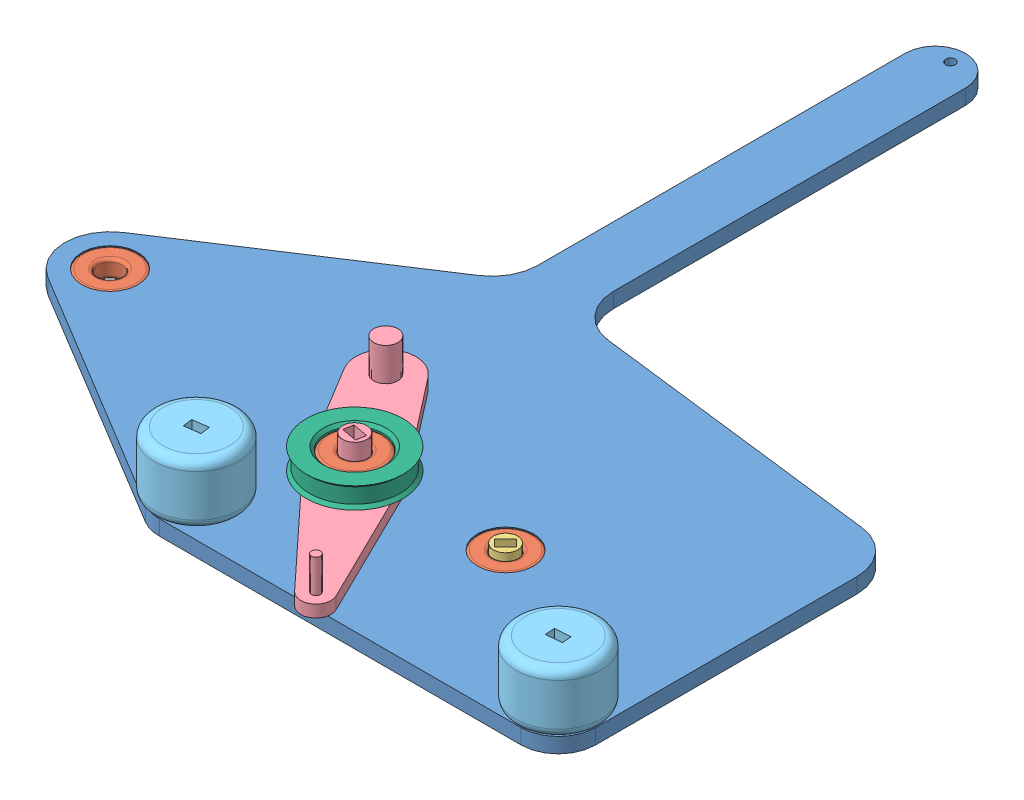
SolidWorks assembly Assem1, configuration Default. Lengths in mm.
Overall size (230.05 31.3 274.17).
13 component instances, 6 part files, 25 mates.
Components (placement in the parent):
- base-1: base [Default] at (141.595 152.7779 330.5532) size (227.3 5 267.3)
- bearing-1: bearing [Default] at (1.595 151.7779 264.2049) size (19 6 19)
- bearing-2: bearing [Default] at (106.2397 151.7779 287.6979) size (19 6 19)
- bearing-3: bearing [Default] at (147.959 151.7779 279.4172) size (19 6 19)
- bearing-4: bearing [Default] at (81.595 151.7779 315.5532) size (19 6 19)
- bearing-5: bearing [Default] at (201.595 151.7779 315.5532) size (19 6 19)
- gear1-1: gear1 [Default] at (106.2397 146.7779 287.6979) x (0.182046 0 -0.98329) z (0.98329 0 0.182046) size (43.58 13 43.58)
- lever1-1: lever1 [Default] at (133.2026 159.7779 336.2734) x (0.98329 0 0.182046) z (-0.182046 0 0.98329) size (78.64 15 78.64)
- wheel-1: wheel [Default] at (81.595 158.0779 315.5532) x (0.991532 0 -0.129866) z (0.129866 0 0.991532) size (28 20 28)
- wheel-2: wheel [Default] at (201.595 158.0779 315.5532) x (0.996928 0 -0.07832) z (0.07832 0 0.996928) size (28 20 28)
- gear1-2: gear1 [Default] at (147.959 146.7779 279.4172) x (0.699396 0 0.714735) z (-0.714735 0 0.699396) size (43.58 13 43.58)
- wheel2-1: wheel2 [Default] at (106.2397 167.2779 287.6979) x (0.999971 0 0.007616) z (-0.007616 0 0.999971) size (32 7 32)
- bearing-6: bearing [Default] at (106.2397 163.7779 287.6979) x (0.996495 0 0.08365) z (-0.08365 0 0.996495) size (19 6 19)
Mates (geometry in assembly coordinates):
- Coincident1: coincident: plane of bearing-5 through (201.595 157.7779 315.5532) normal (0 1 0); plane of base-1 through (81.595 157.7779 315.5532) normal (0 1 0)
- Coincident2: coincident: plane of base-1 through (81.595 157.7779 315.5532) normal (0 1 0); plane of bearing-3 through (147.959 157.7779 279.4172) normal (0 1 0)
- Coincident3: coincident: plane of base-1 through (81.595 157.7779 315.5532) normal (0 1 0); plane of bearing-4 through (81.595 157.7779 315.5532) normal (0 1 0)
- Coincident4: coincident: plane of base-1 through (81.595 157.7779 315.5532) normal (0 1 0); plane of bearing-1 through (1.595 157.7779 264.2049) normal (0 1 0)
- Coincident5: coincident: plane of base-1 through (81.595 157.7779 315.5532) normal (0 1 0); plane of bearing-2 through (106.2397 157.7779 287.6979) normal (0 1 0)
- Concentric1: concentric: cylinder of base-1 through (1.595 157.7779 264.2049) axis (0 -1 0) radius 9.3; cylinder of bearing-1 through (1.595 157.7779 264.2049) axis (0 -1 0) radius 4
- Concentric2: concentric: cylinder of base-1 through (106.2397 157.7779 287.6979) axis (0 -1 0) radius 9.3; cylinder of bearing-2 through (106.2397 157.7779 287.6979) axis (0 -1 0) radius 4
- Concentric3: concentric: cylinder of base-1 through (81.595 157.7779 315.5532) axis (0 -1 0) radius 9.3; cylinder of bearing-4 through (81.595 157.7779 315.5532) axis (0 -1 0) radius 4
- Concentric4: concentric: cylinder of base-1 through (147.959 157.7779 279.4172) axis (0 -1 0) radius 9.3; cylinder of bearing-3 through (147.959 157.7779 279.4172) axis (0 -1 0) radius 4
- Concentric5: concentric: cylinder of base-1 through (201.595 157.7779 315.5532) axis (0 -1 0) radius 9.3; circle of bearing-5
- Distance1: distance = 6 mm aligned: plane of base-1 through (81.595 157.7779 315.5532) normal (0 1 0); plane of gear1-1 through (106.2397 151.7779 287.6979) normal (0 1 0)
- Concentric6: concentric: cylinder of bearing-2 through (106.2397 157.7779 287.6979) axis (0 -1 0) radius 4; cylinder of gear1-1 through (106.2397 159.7779 287.6979) axis (0 -1 0) radius 4
- Coincident11: coincident aligned: plane of gear1-1 through (103.9744 146.7779 285.6513) normal (-0.182046 0 0.98329); plane of lever1-1 through (103.9744 159.7779 285.6513) normal (-0.182046 0 0.98329)
- Coincident12: coincident aligned: plane of gear1-1 through (109.0875 146.7779 286.5979) normal (-0.98329 0 -0.182046); plane of lever1-1 through (108.505 159.7779 289.7444) normal (-0.98329 0 -0.182046)
- Coincident13: coincident anti-aligned: plane of gear1-1 through (106.2397 159.7779 287.6979) normal (0 1 0); plane of lever1-1 through (133.2026 159.7779 336.2734) normal (0 -1 0)
- Concentric7: concentric: cylinder of bearing-4 through (81.595 157.7779 315.5532) axis (0 -1 0) radius 4; cylinder of wheel-1 through (81.595 178.0779 315.5532) axis (0 -1 0) radius 14
- Distance2: distance = 0.3 mm: plane of wheel-1 through (81.595 158.0779 315.5532) normal (0 -1 0); plane of base-1 through (81.595 157.7779 315.5532) normal (0 1 0)
- Concentric8: concentric: cylinder of bearing-5 through (201.595 157.7779 315.5532) axis (0 -1 0) radius 4; cylinder of wheel-2 through (201.595 178.0779 315.5532) axis (0 -1 0) radius 14
- Distance3: distance = 0.3 mm: plane of wheel-2 through (201.595 158.0779 315.5532) normal (0 -1 0); plane of base-1 through (81.595 157.7779 315.5532) normal (0 1 0)
- Coincident16: coincident anti-aligned: cylinder of bearing-3 through (147.959 157.7779 279.4172) axis (0 -1 0) radius 4; circle of gear1-2
- Coincident18: coincident aligned: plane of gear1-1 through (106.2397 146.7779 287.6979) normal (0 -1 0); plane of gear1-2 through (147.959 146.7779 279.4172) normal (0 -1 0)
- Concentric9: concentric aligned: cylinder of lever1-1 through (106.2397 174.7779 287.6979) axis (0 -1 0) radius 4; cylinder of bearing-6 through (106.2397 169.7779 287.6979) axis (0 -1 0) radius 4
- Coincident19: coincident anti-aligned: plane of lever1-1 through (133.2026 163.7779 336.2734) normal (0 1 0); plane of bearing-6 through (106.2397 163.7779 287.6979) normal (0 -1 0)
- Concentric10: concentric aligned: cylinder of wheel2-1 through (106.2397 167.2779 287.6979) axis (0 -1 0) radius 9.5; cylinder of bearing-6 through (106.2397 169.7779 287.6979) axis (0 -1 0) radius 9.5
- Coincident20: coincident anti-aligned: plane of lever1-1 through (133.2026 163.7779 336.2734) normal (0 1 0); plane of wheel2-1 through (115.7394 163.7779 287.7702) normal (0 -1 0)
